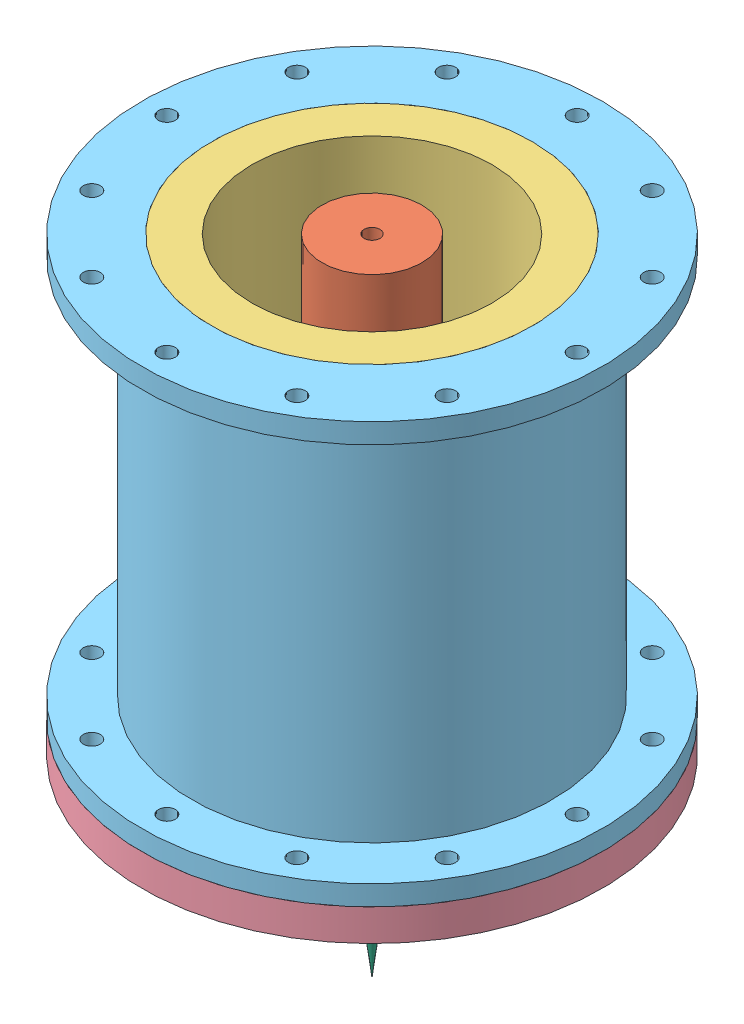
SolidWorks assembly Assem2, configuration Default. Lengths in mm.
Overall size (92.09 128.81 92.09).
6 component instances, 6 part files, 9 mates.
Components (placement in the parent):
- shroud-1: shroud [Default] at (-2.2989 9.5842 -1.1442) size (48 12.84 48)
- spike-1: spike [Default] at (-2.2989 9.5842 -1.1442) x (0.999819 0 -0.019009) z (0.019009 0 0.999819) size (32.89 128.81 32.89)
- insulative liner-1: insulative liner [Default] at (-2.2989 5.5842 -1.1442) size (64 83.98 64)
- base plate-1: base plate [Default] at (-2.2989 -0.7658 -1.1442) x (1 0 -0.00094) z (0.00094 0 1) size (92 6.35 92)
- cylinder wall-1: cylinder wall [Default] at (-2.2989 5.5842 -1.1442) size (92 83.98 92)
- spike tip-1: spike tip [Default] at (-2.2989 9.5842 -1.1442) size (8.29 49.43 18.98)
Mates (geometry in assembly coordinates):
- Concentric1: concentric anti-aligned: cylinder of shroud-1 through (-2.2989 9.5842 -1.1442) axis (0 1 0) radius 15; cylinder of spike-1 through (-2.2989 -39.2416 -1.1442) axis (0 -1 0) radius 10
- Distance2: distance = 18.5 mm aligned: plane of shroud-1 through (-2.2989 5.5842 -1.1442) normal (0 -1 0); plane of spike-1 through (-2.2989 -12.9158 -1.1442) normal (0 -1 0)
- Concentric2: concentric anti-aligned: cylinder of shroud-1 through (-2.2989 9.5842 -1.1442) axis (0 1 0) radius 15; cylinder of insulative liner-1 through (-2.2989 5.5842 -1.1442) axis (0 -1 0) radius 24
- Coincident3: coincident aligned: plane of shroud-1 through (-2.2989 5.5842 -1.1442) normal (0 -1 0); plane of insulative liner-1 through (-2.2989 5.5842 -1.1442) normal (0 -1 0)
- Concentric3: concentric anti-aligned: cylinder of shroud-1 through (-2.2989 9.5842 -1.1442) axis (0 1 0) radius 15; cylinder of cylinder wall-1 through (-2.2989 5.5842 -1.1442) axis (0 -1 0) radius 32
- Coincident4: coincident aligned: plane of insulative liner-1 through (-2.2989 5.5842 -1.1442) normal (0 -1 0); plane of cylinder wall-1 through (-2.2989 5.5842 -1.1442) normal (0 -1 0)
- Concentric4: concentric anti-aligned: cylinder of shroud-1 through (-2.2989 9.5842 -1.1442) axis (0 1 0) radius 15; cylinder of base plate-1 through (-2.2989 -0.7658 -1.1442) axis (0 -1 0) radius 19
- Coincident5: coincident anti-aligned: plane of base plate-1 through (-2.2989 5.5842 -1.1442) normal (0 1 0); plane of cylinder wall-1 through (-2.2989 5.5842 -1.1442) normal (0 -1 0)
- Coincident6: coincident aligned: circle of spike-1; circle of spike tip-1
